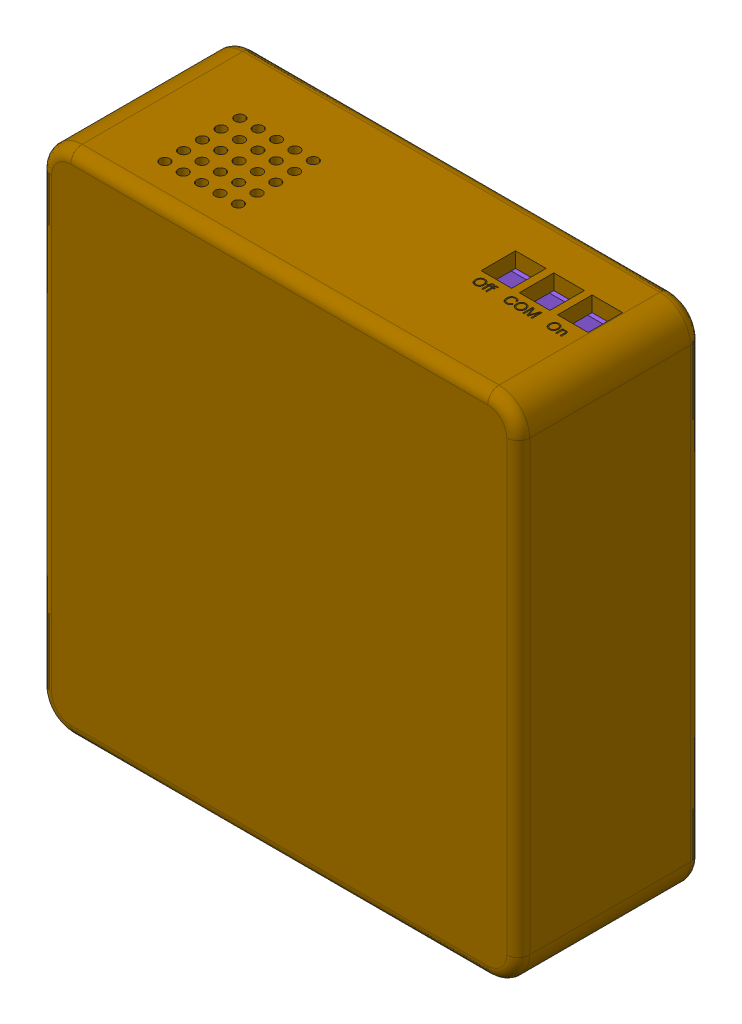
SolidWorks assembly SmokESP8266, configuration Défaut. Lengths in mm.
Overall size (62.5 66.5 25.6).
28 component instances, 11 part files, 8 mates.
Components (placement in the parent):
- SmokESP8266.step-1: SmokESP8266.step [Défaut] at (0 0 2.1188) size (57.77 61.01 23.6)
  - mors_3p.step-1: mors_3p.step [Défaut] at (128.6 -83.93 5.15) x (0 1 0) z (1 0 0) size (7.87 13.75 15.5)
    - COMPOUND.step-1: COMPOUND.step [Défaut] at origin size (7.87 13.75 15.5)
  - relay_srd03vdc-sl-c.step-1: relay_srd03vdc-sl-c.step [Défaut] at (124.46 -93.98 15.15) x (1 0 0) z (0 0 -1) size (19 15 19.51)
    - SOLID.step-1: SOLID.step [Défaut] at origin size (19 15 19.51)
  - B3U1000P.step-1: B3U1000P.step [Défaut] at (83.185 -109.22 1.65) x (1 0 0) z (0 -1 0) size (4 1.6 2.5)
    - COMPOUND-0.step-1: COMPOUND-0.step [Défaut] at origin size (4 1.6 2.5)
  - B3U1000P.step-2: B3U1000P.step [Défaut] at (98.679 -105.537 1.65) x (1 0 0) z (0 -1 0) size (4 1.6 2.5)
    - COMPOUND-0.step-1: COMPOUND-0.step [Défaut] at origin size (4 1.6 2.5)
  - KiCAD-ESP-WROOM-32.step-1: KiCAD-ESP-WROOM-32.step [Défaut] at (124.46 -116.84 1.65) size (18.07 25.54 3.04)
    - COMPOUND-1.step-1: COMPOUND-1.step [Défaut] at origin size (18.07 25.54 3.04)
  - KiCAD-ESP-WROOM-32.step-2: KiCAD-ESP-WROOM-32.step [Défaut] at (124.46 -116.84 1.65) size (18.07 25.54 3.04)
    - COMPOUND-1.step-1: COMPOUND-1.step [Défaut] at origin size (18.07 25.54 3.04)
  - 240240TFT.step-1: 240240TFT.step [Défaut] at (12.59 92.52 -1.55) x (1 0 0) z (0 0 -1) size (25.58 31.66 1.56)
    - SOLID-2.step-1: SOLID-2.step [Défaut] at origin size (25.58 31.66 1.56)
  - mors_2p.step-1: mors_2p.step [Défaut] at (106.358 -125.139 6.15) x (0 -1 0) z (-1 0 0) size (7.87 13.75 10.5)
    - COMPOUND-3.step-1: COMPOUND-3.step [Défaut] at origin size (7.87 13.75 10.5)
  - mors_2p.step-2: mors_2p.step [Défaut] at (86.062 -118.804 6.15) x (-1 0 0) z (0 1 0) size (7.87 13.75 10.5)
    - COMPOUND-3.step-1: COMPOUND-3.step [Défaut] at origin size (7.87 13.75 10.5)
  - mors_2p.step-3: mors_2p.step [Défaut] at (94.035 -125.139 6.15) x (0 -1 0) z (-1 0 0) size (7.87 13.75 10.5)
    - COMPOUND-3.step-1: COMPOUND-3.step [Défaut] at origin size (7.87 13.75 10.5)
  - DHT11-3.step-1: DHT11-3.step [Défaut] at (98.968 -76.803 1.65) x (-1 0 0) z (0 1 0) size (12.54 23.6 5.74)
    - SOLID-4.step-1: SOLID-4.step [Défaut] at origin size (12.54 23.6 5.74)
  - COMPOUND-5.step-1: COMPOUND-5.step [Défaut] at origin size (57.15 60.96 1.6)
- boitier-thermal-1: boitier-thermal [Défaut] at (78.5469 -70.263 19.7688) x (1 0 0) z (0 0 -1) size (62.5 66.5 24)
- vitreacrylic-1: vitreacrylic [Défaut] at (78.5469 -132.763 -2.2312) size (58.5 62.5 3)
- socket head cap screw_ai-26: socket head cap screw_ai [HX-SHCS 0.086-64x0.125x0.125-N] at (82.595 -129.54 -2.8219) x (0 0 1) z (-1 0 0) size (5.36 3.56 3.56)
- socket head cap screw_ai-27: socket head cap screw_ai [HX-SHCS 0.086-64x0.125x0.125-N] at (134.62 -73.66 -2.6861) x (0 0 1) z (-1 0 0) size (5.36 3.56 3.56)
Mates (geometry in assembly coordinates):
- Parallèle2: parallel aligned: plane of SmokESP8266.step-1/COMPOUND-5.step-1; plane of boitier-thermal-1 through (139.0469 -72.263 -2.2312) normal (1 0 0)
- Parallèle3: parallel aligned: plane of SmokESP8266.step-1/relay_srd03vdc-sl-c.step-1/SOLID.step-1; plane of boitier-thermal-1 through (135.0469 -72.263 21.7688) normal (0 0 1)
- Coïncidente3: coincident anti-aligned: plane of SmokESP8266.step-1/DHT11-3.step-1/SOLID-4.step-1; plane of boitier-thermal-1 through (135.0469 -72.263 19.7688) normal (0 0 -1)
- Coïncidente4: coincident anti-aligned: plane of boitier-thermal-1 through (78.5469 -72.263 -2.2312) normal (1 0 0); plane of vitreacrylic-1 through (78.5469 -130.763 0.7688) normal (-1 0 0)
- Coïncidente5: coincident anti-aligned: plane of boitier-thermal-1 through (80.5469 -132.763 -2.2312) normal (0 1 0); plane of vitreacrylic-1 through (80.5469 -132.763 0.7688) normal (0 -1 0)
- Coïncidente6: coincident anti-aligned: line of boitier-thermal-1 through (135.0469 -132.763 -2.2312) axis (-1 0 0); line of vitreacrylic-1 through (80.5469 -132.763 -2.2312) axis (1 0 0)
- Coaxiale381: concentric anti-aligned: cylinder of vitreacrylic-1 through (82.595 -129.54 -7.8812) axis (0 0 1) radius 1.145; cylinder of socket head cap screw_ai-26 through (82.595 -129.54 -34.5719) axis (0 0 -1) radius 1.0922
- Coaxiale391: concentric anti-aligned: cylinder of vitreacrylic-1 through (134.62 -73.66 -7.8812) axis (0 0 1) radius 1.1; cylinder of socket head cap screw_ai-27 through (134.62 -73.66 -34.4361) axis (0 0 -1) radius 1.0922
